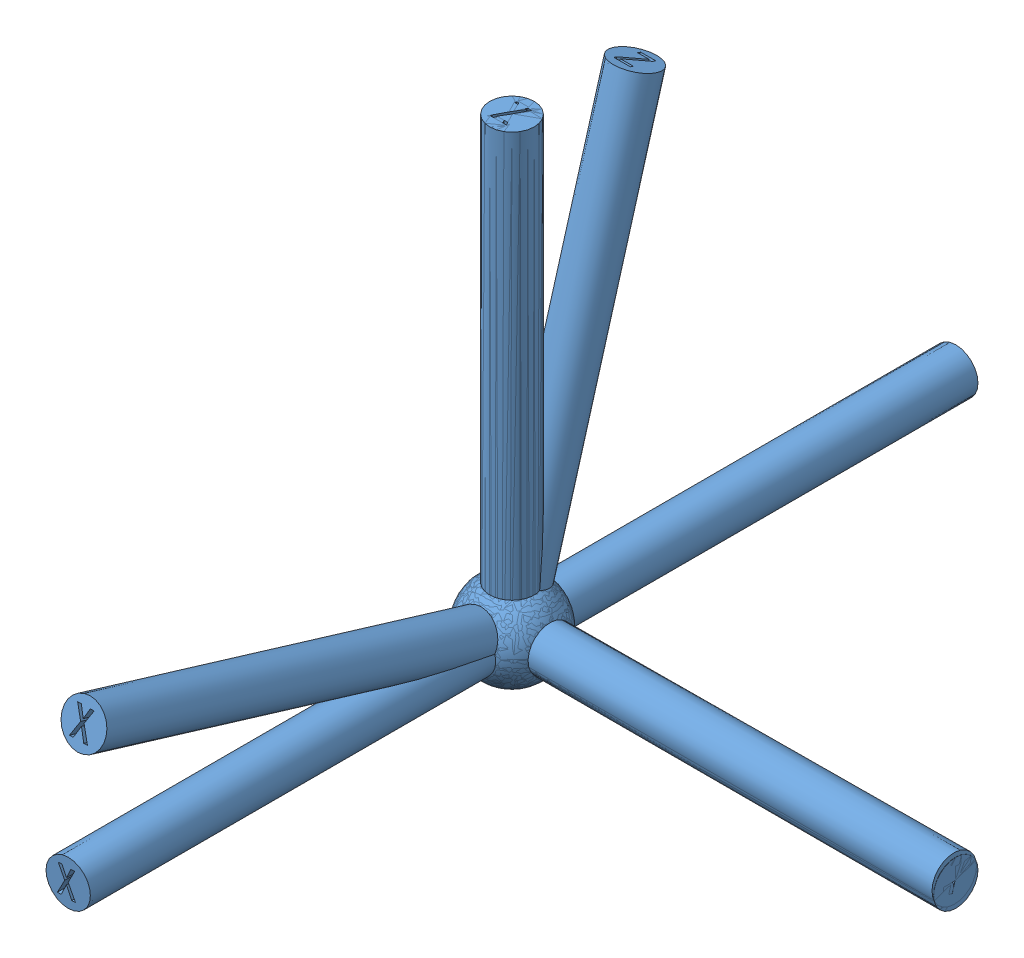
SolidWorks assembly 装配体1, configuration 默认. Lengths in mm.
Overall size (11.16 13.8 20).
3 component instances, 1 part files, 4 mates.
Components (placement in the parent):
- 坐标系-1: 坐标系 [默认] at (-34.4737 19.4875 -4.5) size (11 11 11)
- 坐标系-2: 坐标系 [默认] at (-34.4737 19.4875 -4.5) x (1 0 0) z (0 1 0) size (11 11 11)
- 坐标系-3: 坐标系 [默认] at (-34.4737 19.4875 -4.5) x (0.999942 0.010193 0.003455) z (-0.006225 0.285907 0.958237) size (11 11 11)
Mates (geometry in assembly coordinates):
- 同心2: concentric: sphere of 坐标系-1; sphere of 坐标系-2
- 同心3: concentric: sphere of 坐标系-1; sphere of 坐标系-3
- 同心4: concentric aligned: cylinder of 坐标系-1 through (-34.4737 29.4875 -4.5) axis (0 -1 0) radius 0.5; cylinder of 坐标系-2 through (-34.4737 29.4875 -4.5) axis (0 -1 0) radius 0.5
- 同心5: concentric aligned: cylinder of 坐标系-1 through (-24.4737 19.4875 -4.5) axis (-1 0 0) radius 0.5; cylinder of 坐标系-2 through (-24.4737 19.4875 -4.5) axis (-1 0 0) radius 0.5
